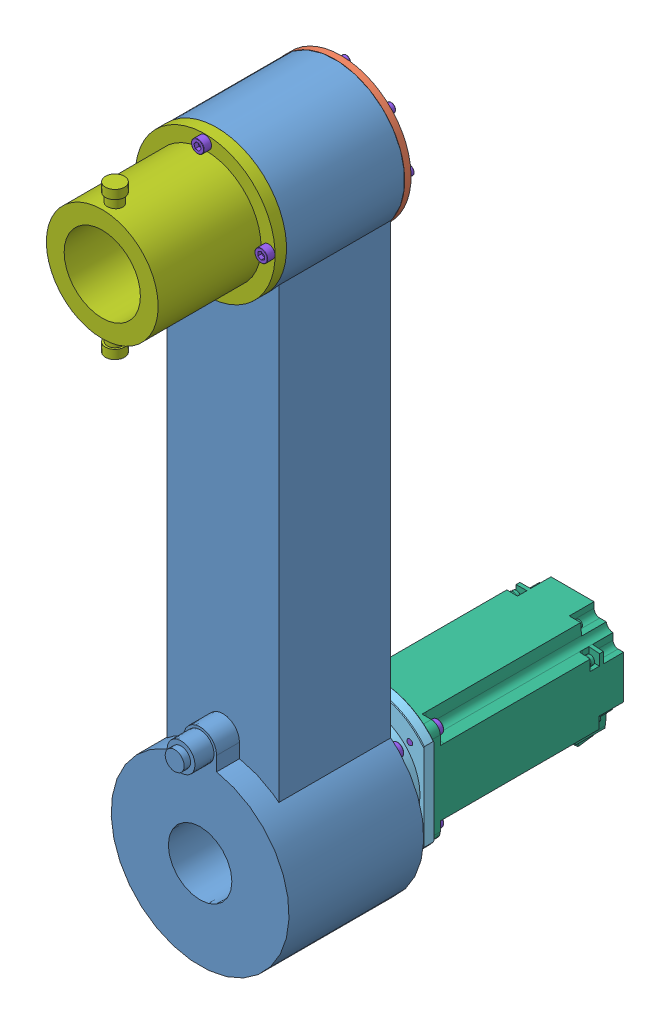
SolidWorks assembly [K2]Assembly, configuration Default. Lengths in mm.
Overall size (140 568 370.3).
36 component instances, 9 part files, 75 mates.
Components (placement in the parent):
- [K2]Thân_3D-1: [K2]Thân_3D [Default] at (157.1441 126.9614 368.742) size (140 565 126)
- [K2]Nắp.stp-1: [K2]Nắp.stp [Default] at (157.1441 566.9614 368.742) x (0 -1 0) z (1 0 0) size (110 23 110)
- [K2]Nắp_che.stp-1: [K2]Nắp_che.stp [Default] at (157.1441 566.9614 344.742) x (0 0 1) z (0 1 0) size (1 56 56)
- [K2]Nắp_Thân.stp-1: [K2]Nắp_Thân.stp [Default] at (157.1441 350.6588 367.742) x (1 0 0) z (0 -1 0) size (80 1 300)
- [K2]Mặt_Bích.stp-1: [K2]Mặt_Bích.stp [Default] at (157.1441 126.9614 368.742) x (1 0 0) z (0 1 0) size (86 35 110)
- [K2]Động_cơ.stp-2: [K2]Động_cơ.stp [Default] at (157.1441 126.9614 333.742) size (80.44 90.82 192.3)
- [K2]Vòng_Cản.stp-2: [K2]Vòng_Cản.stp [Default] at (157.1441 566.9614 551.742) x (0 0 -1) z (1 0 0) size (90 116 110)
- socket head cap screw_iso-3: socket head cap screw_iso [ISO 4762 M4 x 8 - 8S] at (153.9361 523.8651 449.7734) x (0 0 1) z (-1 0 0) size (12 7 7)
- socket head cap screw_iso-4: socket head cap screw_iso [ISO 4762 M4 x 8 - 8S] at (207.1441 566.9614 359.742) x (0 0 1) z (-1 0 0) size (12 7 7)
- socket head cap screw_iso-5: socket head cap screw_iso [ISO 4762 M4 x 8 - 8S] at (192.4994 531.6061 357.9151) x (0 0 1) z (-0.966539 -0.25652 0) size (12 7 7)
- socket head cap screw_iso-6: socket head cap screw_iso [ISO 4762 M4 x 8 - 8S] at (157.1441 616.9614 359.742) x (0 0 1) z (0.010853 -0.999941 0) size (12 7 7)
- socket head cap screw_iso-7: socket head cap screw_iso [ISO 4762 M4 x 8 - 8S] at (121.7887 602.3168 359.742) x (0 0 1) z (0.001298 -0.999999 0) size (12 7 7)
- socket head cap screw_iso-8: socket head cap screw_iso [ISO 4762 M4 x 8 - 8S] at (121.7887 531.6061 359.742) x (0 0 1) z (0.381849 0.924225 0) size (12 7 7)
- socket head cap screw_iso-9: socket head cap screw_iso [ISO 4762 M4 x 8 - 8S] at (192.4994 602.3168 359.742) x (0 0 1) z (-0.985605 -0.169064 0) size (12 7 7)
- socket head cap screw_iso-10: socket head cap screw_iso [ISO 4762 M4 x 8 - 8S] at (157.1441 516.9614 359.742) x (0 0 1) z (0.381849 0.924225 0) size (12 7 7)
- socket head cap screw_iso-11: socket head cap screw_iso [ISO 4762 M4 x 8 - 8S] at (107.1441 566.9614 359.742) x (0 0 1) z (0.381849 0.924225 0) size (12 7 7)
- socket head cap screw_iso-12: socket head cap screw_iso [ISO 4762 M6 x 16 - 16S] at (207.0791 566.9614 476.742) x (0 0 -1) z (1 0 0) size (22 10 10)
- socket head cap screw_iso-13: socket head cap screw_iso [ISO 4762 M6 x 16 - 16S] at (157.1441 616.4614 476.742) x (0 0 -1) z (0.923728 0.383049 0) size (22 10 10)
- socket head cap screw_iso-14: socket head cap screw_iso [ISO 4762 M6 x 16 - 16S] at (107.2091 566.9614 476.742) x (0 0 -1) z (1 0 0) size (22 10 10)
- socket head cap screw_iso-15: socket head cap screw_iso [ISO 4762 M6 x 16 - 16S] at (157.1441 517.4614 476.742) x (0 0 -1) z (1 0 0) size (22 10 10)
- pan head cross recess screw_iso-6: pan head cross recess screw_iso [ISO 7045 - M4 x 8 - Z - 8S] at (192.1441 350.6588 364.642) x (0 0 1) z (-1 0 0) size (11.02 8 8)
- pan head cross recess screw_iso-7: pan head cross recess screw_iso [ISO 7045 - M4 x 8 - Z - 8S] at (122.1441 350.6588 364.642) x (0 0 1) z (-1 0 0) size (11.02 8 8)
- pan head cross recess screw_iso-8: pan head cross recess screw_iso [ISO 7045 - M4 x 8 - Z - 8S] at (122.1441 495.6588 364.642) x (0 0 1) z (-1 0 0) size (11.02 8 8)
- pan head cross recess screw_iso-9: pan head cross recess screw_iso [ISO 7045 - M4 x 8 - Z - 8S] at (192.1441 495.6588 364.642) x (0 0 1) z (-1 0 0) size (11.02 8 8)
- pan head cross recess screw_iso-10: pan head cross recess screw_iso [ISO 7045 - M4 x 8 - Z - 8S] at (192.1441 205.6588 364.642) x (0 0 1) z (-1 0 0) size (11.02 8 8)
- pan head cross recess screw_iso-11: pan head cross recess screw_iso [ISO 7045 - M4 x 8 - Z - 8S] at (122.1441 205.6588 364.642) x (0 0 1) z (-1 0 0) size (11.02 8 8)
- socket head cap screw_iso-16: socket head cap screw_iso [ISO 4762 M6 x 16 - 16S] at (121.7887 162.3168 354.742) x (0 0 1) z (-1 0 0) size (22 10 10)
- socket head cap screw_iso-17: socket head cap screw_iso [ISO 4762 M6 x 16 - 16S] at (125.3243 158.7812 319.742) x (0 0 1) z (-1 0 0) size (22 10 10)
- socket head cap screw_iso-18: socket head cap screw_iso [ISO 4762 M6 x 16 - 16S] at (192.4994 162.3168 354.742) x (0 0 1) z (-1 0 0) size (22 10 10)
- socket head cap screw_iso-19: socket head cap screw_iso [ISO 4762 M6 x 16 - 16S] at (188.9639 158.7812 319.742) x (0 0 1) z (-1 0 0) size (22 10 10)
- socket head cap screw_iso-20: socket head cap screw_iso [ISO 4762 M6 x 16 - 16S] at (192.4994 91.6061 354.742) x (0 0 1) z (-1 0 0) size (22 10 10)
- socket head cap screw_iso-21: socket head cap screw_iso [ISO 4762 M6 x 16 - 16S] at (188.9639 95.1416 319.742) x (0 0 1) z (-1 0 0) size (22 10 10)
- socket head cap screw_iso-22: socket head cap screw_iso [ISO 4762 M6 x 16 - 16S] at (125.3243 95.1416 319.742) x (0 0 1) z (-1 0 0) size (22 10 10)
- socket head cap screw_iso-23: socket head cap screw_iso [ISO 4762 M6 x 16 - 16S] at (121.7887 91.6061 354.742) x (0 0 1) z (-1 0 0) size (22 10 10)
- pan head cross recess screw_iso-12: pan head cross recess screw_iso [ISO 7045 - M3 x 5 - Z - 5N] at (157.1441 590.9614 342.342) x (0 0 1) z (-1 0 0) size (7.35 5.6 5.6)
- pan head cross recess screw_iso-13: pan head cross recess screw_iso [ISO 7045 - M3 x 5 - Z - 5N] at (157.1441 542.9614 342.342) x (0 0 1) z (-1 0 0) size (7.35 5.6 5.6)
Mates (geometry in assembly coordinates):
- Coincident1: coincident anti-aligned: plane of [K2]Thân_3D-1 through (157.1441 126.9614 368.742) normal (0 0 -1); plane of [K2]Nắp.stp-1 through (157.1441 566.9614 368.742) normal (0 0 1)
- Concentric3: concentric anti-aligned: circle of [K2]Thân_3D-1; circle of [K2]Nắp.stp-1
- Coincident6: coincident anti-aligned: plane of [K2]Thân_3D-1 through (157.1441 126.9614 368.742) normal (0 0 -1); plane of [K2]Nắp_Thân.stp-1 through (157.1441 350.6588 368.742) normal (0 0 1)
- Concentric6: concentric anti-aligned: circle of [K2]Thân_3D-1; circle of [K2]Nắp_Thân.stp-1
- Coincident9: coincident anti-aligned: plane of [K2]Nắp.stp-1 through (129.1441 566.9614 345.742) normal (0 0 -1); plane of [K2]Nắp_che.stp-1 through (157.1441 566.9614 345.742) normal (0 0 1)
- Concentric8: concentric aligned: circle of [K2]Nắp.stp-1; circle of [K2]Nắp_che.stp-1
- Coincident10: coincident anti-aligned: cylinder of [K2]Thân_3D-1; cylinder of [K2]Mặt_Bích.stp-1 through (157.1441 126.9614 351.242) axis (0 0 1) radius 35
- Concentric9: concentric anti-aligned: circle of [K2]Thân_3D-1; circle of [K2]Mặt_Bích.stp-1
- Coincident11: coincident anti-aligned: plane of [K2]Thân_3D-1 through (157.1441 126.9614 368.742) normal (0 0 -1); plane of [K2]Mặt_Bích.stp-1 through (157.1441 91.9614 368.742) normal (0 0 1)
- Concentric13: concentric anti-aligned: circle of [K2]Thân_3D-1; circle of [K2]Nắp.stp-1
- Concentric14: concentric aligned: circle of [K2]Nắp.stp-1; circle of [K2]Nắp_che.stp-1
- Concentric15: concentric aligned: circle of [K2]Mặt_Bích.stp-1; cylinder of [K2]Động_cơ.stp-2 through (157.1441 126.9614 355.742) axis (0 0 1) radius 9.5
- Concentric16: concentric anti-aligned: circle of [K2]Mặt_Bích.stp-1; circle of [K2]Động_cơ.stp-2
- Coincident18: coincident anti-aligned: plane of [K2]Mặt_Bích.stp-1 through (157.1441 71.9614 333.742) normal (0 0 -1); plane of [K2]Động_cơ.stp-2 through (157.1441 126.9614 333.742) normal (0 0 1)
- Coincident19: coincident anti-aligned: plane of [K2]Thân_3D-1 through (157.1441 566.9614 461.742) normal (0 0 1); plane of [K2]Vòng_Cản.stp-2 through (157.1441 566.9614 461.742) normal (0 0 -1)
- Concentric17: concentric anti-aligned: circle of [K2]Thân_3D-1; circle of [K2]Vòng_Cản.stp-2
- Parallel4: parallel aligned: plane of [K2]Vòng_Cản.stp-2 through (157.1441 624.9614 541.742) normal (0 1 0)
- Coincident25: coincident anti-aligned: plane of [K2]Nắp.stp-1 through (157.1441 566.9614 363.742) normal (0 0 -1); plane of socket head cap screw_iso-4 through (207.1441 570.4614 363.742) normal (0 0 1)
- Coincident26: coincident aligned: plane of [K2]Nắp.stp-1 through (157.1441 566.9614 363.742) normal (0 0 -1); circle of socket head cap screw_iso-9
- Coincident27: coincident anti-aligned: circle of socket head cap screw_iso-6; plane of socket head cap screw_iso-7 through (118.2887 602.3122 363.742) normal (0 0 1)
- Coincident28: coincident anti-aligned: circle of [K2]Nắp.stp-1; circle of socket head cap screw_iso-5
- Concentric19: concentric anti-aligned: circle of [K2]Nắp.stp-1; circle of socket head cap screw_iso-4
- Concentric20: concentric anti-aligned: circle of [K2]Nắp.stp-1; circle of socket head cap screw_iso-5
- Coincident29: coincident aligned: circle of [K2]Nắp.stp-1; plane of socket head cap screw_iso-6 through (153.6443 616.9235 363.742) normal (0 0 1)
- Concentric21: concentric anti-aligned: circle of [K2]Nắp.stp-1; circle of socket head cap screw_iso-6
- Concentric22: concentric anti-aligned: circle of [K2]Nắp.stp-1; circle of socket head cap screw_iso-9
- Coincident30: coincident anti-aligned: plane of [K2]Nắp.stp-1 through (157.1441 566.9614 363.742) normal (0 0 -1); plane of socket head cap screw_iso-7 through (118.2887 602.3122 363.742) normal (0 0 1)
- Concentric23: concentric anti-aligned: circle of [K2]Nắp.stp-1; circle of socket head cap screw_iso-7
- Coincident31: coincident anti-aligned: plane of [K2]Nắp.stp-1 through (157.1441 566.9614 363.742) normal (0 0 -1); plane of socket head cap screw_iso-11 through (110.3788 565.625 363.742) normal (0 0 1)
- Concentric24: concentric anti-aligned: circle of [K2]Nắp.stp-1; circle of socket head cap screw_iso-11
- Coincident32: coincident anti-aligned: plane of [K2]Nắp.stp-1 through (157.1441 566.9614 363.742) normal (0 0 -1); plane of socket head cap screw_iso-8 through (125.0235 530.2696 363.742) normal (0 0 1)
- Concentric25: concentric anti-aligned: circle of [K2]Nắp.stp-1; circle of socket head cap screw_iso-8
- Coincident33: coincident anti-aligned: plane of [K2]Nắp.stp-1 through (157.1441 566.9614 363.742) normal (0 0 -1); plane of socket head cap screw_iso-10 through (160.3788 515.625 363.742) normal (0 0 1)
- Concentric26: concentric anti-aligned: circle of [K2]Nắp.stp-1; circle of socket head cap screw_iso-10
- Coincident34: coincident anti-aligned: plane of [K2]Vòng_Cản.stp-2 through (157.1441 566.9614 470.742) normal (0 0 1); plane of socket head cap screw_iso-13 through (155.2288 621.0801 470.742) normal (0 0 -1)
- Concentric27: concentric anti-aligned: circle of [K2]Vòng_Cản.stp-2; circle of socket head cap screw_iso-13
- Coincident35: coincident anti-aligned: plane of [K2]Vòng_Cản.stp-2 through (157.1441 566.9614 470.742) normal (0 0 1); plane of socket head cap screw_iso-12 through (207.0791 571.9614 470.742) normal (0 0 -1)
- Concentric28: concentric anti-aligned: circle of [K2]Vòng_Cản.stp-2; circle of socket head cap screw_iso-12
- Coincident36: coincident anti-aligned: plane of [K2]Vòng_Cản.stp-2 through (157.1441 566.9614 470.742) normal (0 0 1); plane of socket head cap screw_iso-14 through (107.2091 571.9614 470.742) normal (0 0 -1)
- Concentric29: concentric anti-aligned: circle of [K2]Vòng_Cản.stp-2; circle of socket head cap screw_iso-14
- Coincident37: coincident anti-aligned: plane of [K2]Vòng_Cản.stp-2 through (157.1441 566.9614 470.742) normal (0 0 1); plane of socket head cap screw_iso-15 through (157.1441 522.4614 470.742) normal (0 0 -1)
- Concentric30: concentric anti-aligned: circle of [K2]Vòng_Cản.stp-2; circle of socket head cap screw_iso-15
- Coincident38: coincident anti-aligned: cylinder of [K2]Thân_3D-1 through (122.1441 205.6588 368.742) axis (0 0 -1) radius 2; circle of [K2]Nắp_Thân.stp-1
- Concentric32: concentric anti-aligned: cylinder of [K2]Nắp_Thân.stp-1 through (192.1441 350.6588 58.2569) axis (0 0 1) radius 2; cylinder of pan head cross recess screw_iso-6 through (192.1441 350.6588 339.242) axis (0 0 -1) radius 4
- Coincident40: coincident anti-aligned: plane of [K2]Nắp_Thân.stp-1 through (157.1441 350.6588 367.742) normal (0 0 -1); plane of pan head cross recess screw_iso-6 through (192.1441 352.6588 367.742) normal (0 0 1)
- Concentric33: concentric anti-aligned: cylinder of [K2]Nắp_Thân.stp-1 through (122.1441 350.6588 58.2569) axis (0 0 1) radius 2; cylinder of pan head cross recess screw_iso-7 through (122.1441 350.6588 339.242) axis (0 0 -1) radius 4
- Coincident41: coincident anti-aligned: plane of [K2]Nắp_Thân.stp-1 through (157.1441 350.6588 367.742) normal (0 0 -1); plane of pan head cross recess screw_iso-7 through (122.1441 352.6588 367.742) normal (0 0 1)
- Concentric34: concentric anti-aligned: cylinder of [K2]Nắp_Thân.stp-1 through (122.1441 495.6588 58.2569) axis (0 0 1) radius 2; cylinder of pan head cross recess screw_iso-8 through (122.1441 495.6588 339.242) axis (0 0 -1) radius 4
- Coincident42: coincident anti-aligned: plane of [K2]Nắp_Thân.stp-1 through (157.1441 350.6588 367.742) normal (0 0 -1); plane of pan head cross recess screw_iso-8 through (122.1441 497.6588 367.742) normal (0 0 1)
- Concentric35: concentric anti-aligned: cylinder of [K2]Nắp_Thân.stp-1 through (192.1441 495.6588 58.2569) axis (0 0 1) radius 2; cylinder of pan head cross recess screw_iso-9 through (192.1441 495.6588 339.242) axis (0 0 -1) radius 4
- Coincident43: coincident anti-aligned: plane of [K2]Nắp_Thân.stp-1 through (157.1441 350.6588 367.742) normal (0 0 -1); plane of pan head cross recess screw_iso-9 through (192.1441 497.6588 367.742) normal (0 0 1)
- Concentric36: concentric anti-aligned: cylinder of [K2]Nắp_Thân.stp-1 through (192.1441 205.6588 58.2569) axis (0 0 1) radius 2; cylinder of pan head cross recess screw_iso-10 through (192.1441 205.6588 339.242) axis (0 0 -1) radius 4
- Coincident44: coincident anti-aligned: plane of [K2]Nắp_Thân.stp-1 through (157.1441 350.6588 367.742) normal (0 0 -1); plane of pan head cross recess screw_iso-10 through (192.1441 207.6588 367.742) normal (0 0 1)
- Concentric37: concentric anti-aligned: cylinder of [K2]Nắp_Thân.stp-1 through (122.1441 205.6588 58.2569) axis (0 0 1) radius 2; cylinder of pan head cross recess screw_iso-11 through (122.1441 205.6588 339.242) axis (0 0 -1) radius 4
- Coincident45: coincident anti-aligned: plane of [K2]Nắp_Thân.stp-1 through (157.1441 350.6588 367.742) normal (0 0 -1); plane of pan head cross recess screw_iso-11 through (122.1441 207.6588 367.742) normal (0 0 1)
- Concentric38: concentric anti-aligned: cylinder of [K2]Mặt_Bích.stp-1 through (121.7887 162.3168 209.2898) axis (0 0 1) radius 2; cylinder of socket head cap screw_iso-16 through (121.7887 162.3168 322.992) axis (0 0 -1) radius 5
- Coincident46: coincident anti-aligned: plane of [K2]Mặt_Bích.stp-1 through (157.1441 71.9614 360.742) normal (0 0 -1); plane of socket head cap screw_iso-16 through (121.7887 167.3168 360.742) normal (0 0 1)
- Concentric39: concentric aligned: cylinder of [K2]Động_cơ.stp-2 through (125.3243 158.7812 324.242) axis (0 0 -1) radius 6.5; cylinder of socket head cap screw_iso-17 through (125.3243 158.7812 287.992) axis (0 0 -1) radius 5
- Coincident47: coincident anti-aligned: plane of [K2]Động_cơ.stp-2 through (124.4842 159.6213 325.742) normal (0 0 -1); plane of socket head cap screw_iso-17 through (125.3243 163.7812 325.742) normal (0 0 1)
- Concentric40: concentric anti-aligned: cylinder of [K2]Mặt_Bích.stp-1 through (192.4994 162.3168 209.2898) axis (0 0 1) radius 2; cylinder of socket head cap screw_iso-18 through (192.4994 162.3168 322.992) axis (0 0 -1) radius 5
- Coincident48: coincident anti-aligned: plane of [K2]Mặt_Bích.stp-1 through (157.1441 71.9614 360.742) normal (0 0 -1); plane of socket head cap screw_iso-18 through (192.4994 167.3168 360.742) normal (0 0 1)
- Concentric41: concentric anti-aligned: cylinder of [K2]Động_cơ.stp-2 through (188.9639 158.7812 329.742) axis (0 0 1) radius 3.3; cylinder of socket head cap screw_iso-19 through (188.9639 158.7812 287.992) axis (0 0 -1) radius 5
- Coincident49: coincident anti-aligned: plane of [K2]Động_cơ.stp-2 through (189.804 159.6213 325.742) normal (0 0 -1); plane of socket head cap screw_iso-19 through (188.9639 163.7812 325.742) normal (0 0 1)
- Concentric42: concentric anti-aligned: cylinder of [K2]Mặt_Bích.stp-1 through (192.4994 91.6061 209.2898) axis (0 0 1) radius 2; cylinder of socket head cap screw_iso-20 through (192.4994 91.6061 322.992) axis (0 0 -1) radius 5
- Coincident50: coincident anti-aligned: plane of [K2]Mặt_Bích.stp-1 through (157.1441 71.9614 360.742) normal (0 0 -1); plane of socket head cap screw_iso-20 through (192.4994 96.6061 360.742) normal (0 0 1)
- Concentric43: concentric anti-aligned: cylinder of [K2]Động_cơ.stp-2 through (188.9639 95.1416 329.742) axis (0 0 1) radius 3.3; cylinder of socket head cap screw_iso-21 through (188.9639 95.1416 287.992) axis (0 0 -1) radius 5
- Coincident51: coincident anti-aligned: plane of [K2]Động_cơ.stp-2 through (189.804 94.3015 325.742) normal (0 0 -1); plane of socket head cap screw_iso-21 through (188.9639 100.1416 325.742) normal (0 0 1)
- Concentric44: concentric anti-aligned: cylinder of [K2]Động_cơ.stp-2 through (125.3243 95.1416 329.742) axis (0 0 1) radius 3.3; cylinder of socket head cap screw_iso-22 through (125.3243 95.1416 287.992) axis (0 0 -1) radius 5
- Coincident52: coincident anti-aligned: plane of [K2]Động_cơ.stp-2 through (124.4842 94.3015 325.742) normal (0 0 -1); plane of socket head cap screw_iso-22 through (125.3243 100.1416 325.742) normal (0 0 1)
- Concentric45: concentric anti-aligned: cylinder of [K2]Mặt_Bích.stp-1 through (121.7887 91.6061 209.2898) axis (0 0 1) radius 2; cylinder of socket head cap screw_iso-23 through (121.7887 91.6061 322.992) axis (0 0 -1) radius 5
- Coincident53: coincident anti-aligned: plane of [K2]Mặt_Bích.stp-1 through (157.1441 71.9614 360.742) normal (0 0 -1); plane of socket head cap screw_iso-23 through (121.7887 96.6061 360.742) normal (0 0 1)
- Concentric46: concentric anti-aligned: cylinder of [K2]Nắp_che.stp-1 through (157.1441 590.9614 266.5397) axis (0 0 1) radius 2; cylinder of pan head cross recess screw_iso-12 through (157.1441 590.9614 316.942) axis (0 0 -1) radius 2.8
- Coincident54: coincident anti-aligned: plane of [K2]Nắp_che.stp-1 through (157.1441 566.9614 344.742) normal (0 0 -1); plane of pan head cross recess screw_iso-12 through (157.1441 592.4614 344.742) normal (0 0 1)
- Concentric47: concentric anti-aligned: cylinder of [K2]Nắp_che.stp-1 through (157.1441 542.9614 266.5397) axis (0 0 1) radius 2; cylinder of pan head cross recess screw_iso-13 through (157.1441 542.9614 316.942) axis (0 0 -1) radius 2.8
- Coincident55: coincident anti-aligned: plane of [K2]Nắp_che.stp-1 through (157.1441 566.9614 344.742) normal (0 0 -1); plane of pan head cross recess screw_iso-13 through (157.1441 544.4614 344.742) normal (0 0 1)
